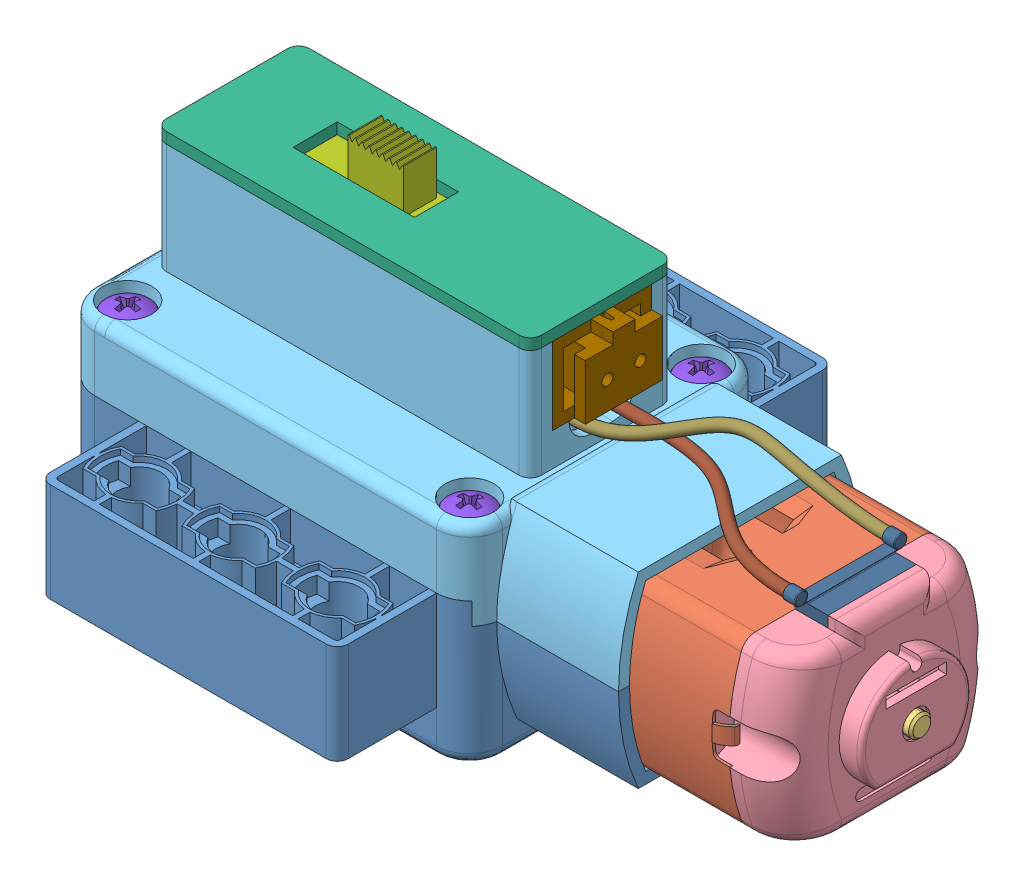
SolidWorks assembly Subconjunto motor, configuration Default. Lengths in mm.
Overall size (65.29 37.9 45).
23 component instances, 18 part files, 60 mates.
Components (placement in the parent):
- Caixa motor superior-1: Caixa motor superior [Default] at (12.9584 20.6455 40.0597) size (48 14.5 45)
- Carcaça-1: Carcaça [Default] at (41.4584 25.1455 40.0597) size (21 15 20.02)
- Veio rotor-1: Veio rotor [Default] at (40.9584 25.1455 40.0597) x (1 0 0) z (0 -0.655557 -0.755146) size (36 2 2)
- Tampa-1: Tampa [Default] at (52.4584 25.1455 40.0597) x (-1 0 0) z (0 0 -1) size (10.02 16 20.34)
- Caixa motor inferior-1: Caixa motor inferior [Default] at (12.9584 33.1455 40.0597) x (1 0 0) z (0 0 -1) size (48 22 27)
- Capa interruptor-1: Capa interruptor [Default] at (12.9584 43.1455 40.0597) size (34 8 13)
- Interruptor-1: Interruptor [Default] at (10.9428 42.1455 40.0597) size (18 5 6)
- pan head cross recess screw_iso-1: pan head cross recess screw_iso [ISO 7045 - M2 x 12 - Z - 12N] at (-2.5416 32.9855 50.5597) x (0 -1 0) z (0 0 1) size (13.57 4 4)
- pan head cross recess screw_iso-2: pan head cross recess screw_iso [ISO 7045 - M2 x 12 - Z - 12N] at (28.4584 32.9855 50.5597) x (0 -1 0) z (-0.094826 0 0.995494) size (13.57 4 4)
- pan head cross recess screw_iso-3: pan head cross recess screw_iso [ISO 7045 - M2 x 12 - Z - 12N] at (28.4584 32.9855 29.5597) x (0 -1 0) z (0 0 1) size (13.57 4 4)
- pan head cross recess screw_iso-4: pan head cross recess screw_iso [ISO 7045 - M2 x 12 - Z - 12N] at (-2.5416 32.9855 29.5597) x (0 -1 0) z (0 0 1) size (13.57 4 4)
- Ficha-1: Ficha [Default] at (31.9584 39.6455 40.0597) x (-1 0 0) z (0 0 -1) size (9 7 9)
- Terminais motor-1: Terminais motor [Default] at (52.9584 32.7705 40.0597) size (3 2.95 10.2)
- Part14^Subconjunto motor-1: Part14^Subconjunto motor [Default] at (27.9584 33.1455 40.0597) x (0 0 1) z (1 0 0) size (7.51 1.91 24.5)
- Part15^Subconjunto motor-1: Part15^Subconjunto motor [Default] at (27.9584 33.1455 40.0597) x (0 0 1) z (1 0 0) size (7.38 2.7 24.5)
- Veios interiores motor-1: Veios interiores motor [Veio cilindro menor] at (16.9584 22.6455 40.0597) x (0 1 0) z (0.959634 0 0.281251) size (19 2 2)
- Veios interiores motor-2: Veios interiores motor [Veio cilindro maior] at (5.9584 24.6955 40.0597) x (0 1 0) z (0 0 1) size (14.9 2 2)
- Engrenagem veio rotor-1: Engrenagem veio rotor [Default] at (25.6584 25.1455 40.0597) x (0 -0.542188 0.840257) z (0 -0.840257 -0.542188) size (6 5.02 6.03)
- 1º Engrenagem-1: 1º Engrenagem [Default] at (16.9584 29.7455 40.0597) x (-0.306597 0 -0.951839) z (-0.951839 0 0.306597) size (17.01 7.3 17.01)
- 2º e 3º Engrenagem-1: 2º e 3º Engrenagem [Default] at (5.9584 25.7455 40.0597) x (0.717197 0 -0.696871) z (-0.696871 0 -0.717197) size (17.4 6.4 17.38)
- 2º e 3º Engrenagem-2: 2º e 3º Engrenagem [Default] at (16.9584 22.0455 40.0597) x (-0.204507 0 -0.978865) z (-0.978865 0 0.204507) size (17.4 6.4 17.38)
- 4º Engrenagem-1: 4º Engrenagem [Default] at (5.9584 19.7455 40.0597) x (0.389423 0 -0.921059) z (-0.921059 0 -0.389423) size (17.4 3 17.4)
- Engrenagem saída do motor-1: Engrenagem saída do motor [Default] at (5.9584 18.2455 40.0597) x (0.962914 0 -0.269808) z (-0.269808 0 -0.962914) size (11.75 9 11.02)
Mates (geometry in assembly coordinates):
- Concentric1: concentric anti-aligned: cylinder of Carcaça-1 through (30.4584 25.1455 40.0597) axis (1 0 0) radius 3; cylinder of Veio rotor-1 through (22.9584 25.1455 40.0597) axis (-1 0 0) radius 1
- Concentric2: concentric anti-aligned: cylinder of Carcaça-1 through (30.4584 25.1455 40.0597) axis (1 0 0) radius 3; cylinder of Tampa-1 through (58.4584 25.1455 40.0597) axis (-1 0 0) radius 5
- Coincident1: coincident aligned: plane of Carcaça-1 through (51.4584 32.6455 48.6002) normal (0 1 0); plane of Tampa-1 through (48.4584 32.6455 31.5192) normal (0 1 0)
- Coincident2: coincident anti-aligned: plane of Carcaça-1 through (51.4584 25.1455 50.0597) normal (1 0 0); plane of Tampa-1 through (51.4584 17.6455 44.0597) normal (-1 0 0)
- Concentric3: concentric anti-aligned: cylinder of Caixa motor superior-1 through (-5.5426 25.1455 40.0597) axis (1 0 0) radius 3; cylinder of Veio rotor-1 through (22.9584 25.1455 40.0597) axis (-1 0 0) radius 1
- Coincident4: coincident aligned: plane of Caixa motor superior-1 through (30.4584 27.1455 50.5597) normal (-1 0 0); plane of Carcaça-1 through (30.4584 25.1455 40.0597) normal (-1 0 0)
- Distance1: distance = 0.5 mm aligned: plane of Tampa-1 through (58.4584 25.1455 40.0597) normal (1 0 0); plane of Veio rotor-1 through (58.9584 25.1455 40.0597) normal (1 0 0)
- Concentric4: concentric anti-aligned: cylinder of Caixa motor superior-1 through (18.4584 27.1455 28.5097) axis (0 -1 0) radius 1; cylinder of Caixa motor inferior-1 through (18.4584 21.1455 28.5097) axis (0 1 0) radius 1
- Concentric5: concentric anti-aligned: cylinder of Caixa motor superior-1 through (7.4584 27.1455 51.6097) axis (0 -1 0) radius 1; cylinder of Caixa motor inferior-1 through (7.4584 21.1455 51.6097) axis (0 1 0) radius 1
- Coincident6: coincident anti-aligned: plane of Caixa motor superior-1 through (28.4584 27.1455 50.5597) normal (0 1 0); plane of Caixa motor inferior-1 through (28.4584 27.1455 50.5597) normal (0 -1 0)
- Width1: width anti-aligned: plane of Capa interruptor-1 through (3.9584 36.1455 38.0597) normal (0 0 1); plane of Capa interruptor-1 through (3.9584 36.1455 42.0597) normal (0 0 -1); plane of Interruptor-1 through (8.4428 47.1455 38.5597) normal (0 0 -1); plane of Interruptor-1 through (8.4428 47.1455 41.5597) normal (0 0 1)
- Coincident7: coincident anti-aligned: plane of Capa interruptor-1 through (28.9584 43.1455 34.5597) normal (0 -1 0); plane of Interruptor-1 through (10.9428 43.1455 40.0597) normal (0 1 0)
- LimitDistance1: limit distance = 1.5156 mm anti-aligned: plane of Interruptor-1 through (13.4428 47.1455 38.5597) normal (1 0 0); plane of Capa interruptor-1 through (14.9584 36.1455 42.0597) normal (-1 0 0)
- Concentric6: concentric anti-aligned: cylinder of Caixa motor inferior-1 through (-2.2916 46.1455 44.8097) axis (0 -1 0) radius 0.5; cylinder of Capa interruptor-1 through (-2.2916 36.1455 44.8097) axis (0 1 0) radius 0.5
- Concentric7: concentric anti-aligned: cylinder of Caixa motor inferior-1 through (21.2084 46.1455 35.3097) axis (0 -1 0) radius 0.5; cylinder of Capa interruptor-1 through (21.2084 36.1455 35.3097) axis (0 1 0) radius 0.5
- Coincident8: coincident anti-aligned: plane of Caixa motor inferior-1 through (-3.0416 43.1455 34.5597) normal (0 1 0); plane of Capa interruptor-1 through (28.9584 43.1455 34.5597) normal (0 -1 0)
- Concentric8: concentric aligned: cylinder of Caixa motor inferior-1 through (-2.5416 33.1455 50.5597) axis (0 1 0) radius 1.2; cylinder of pan head cross recess screw_iso-1 through (-2.5416 58.3855 50.5597) axis (0 1 0) radius 2
- Coincident9: coincident anti-aligned: plane of Caixa motor inferior-1 through (-2.5416 31.3855 50.5597) normal (0 1 0); plane of pan head cross recess screw_iso-1 through (-1.5416 31.3855 50.5597) normal (0 -1 0)
- Concentric9: concentric aligned: cylinder of Caixa motor inferior-1 through (28.4584 33.1455 50.5597) axis (0 1 0) radius 1.2; cylinder of pan head cross recess screw_iso-2 through (28.4584 58.3855 50.5597) axis (0 1 0) radius 2
- Coincident10: coincident anti-aligned: plane of Caixa motor inferior-1 through (28.4584 31.3855 50.5597) normal (0 1 0); plane of pan head cross recess screw_iso-2 through (29.4539 31.3855 50.6545) normal (0 -1 0)
- Concentric10: concentric aligned: cylinder of Caixa motor inferior-1 through (28.4584 33.1455 29.5597) axis (0 1 0) radius 1.2; cylinder of pan head cross recess screw_iso-3 through (28.4584 58.3855 29.5597) axis (0 1 0) radius 2
- Coincident11: coincident anti-aligned: plane of Caixa motor inferior-1 through (28.4584 31.3855 29.5597) normal (0 1 0); plane of pan head cross recess screw_iso-3 through (29.4584 31.3855 29.5597) normal (0 -1 0)
- Concentric11: concentric aligned: cylinder of Caixa motor inferior-1 through (-2.5416 33.1455 29.5597) axis (0 1 0) radius 1.2; cylinder of pan head cross recess screw_iso-4 through (-2.5416 58.3855 29.5597) axis (0 1 0) radius 2
- Coincident12: coincident anti-aligned: plane of Caixa motor inferior-1 through (-2.5416 31.3855 29.5597) normal (0 1 0); plane of pan head cross recess screw_iso-4 through (-1.5416 31.3855 29.5597) normal (0 -1 0)
- Coincident13: coincident anti-aligned: plane of Caixa motor inferior-1 through (22.9584 33.1455 40.0597) normal (1 0 0); plane of Ficha-1 through (22.9584 39.6455 40.0597) normal (-1 0 0)
- Coincident14: coincident anti-aligned: plane of Caixa motor inferior-1 through (22.9584 43.1455 44.5597) normal (0 0 -1); plane of Ficha-1 through (29.9584 36.1455 44.5597) normal (0 0 1)
- Coincident15: coincident anti-aligned: plane of Caixa motor inferior-1 through (22.9584 36.1455 35.5597) normal (0 1 0); plane of Ficha-1 through (29.9584 36.1455 44.5597) normal (0 -1 0)
- Concentric12: concentric anti-aligned: cylinder of Tampa-1 through (54.4584 32.7705 40.0597) axis (1 0 0) radius 0.5; cylinder of Terminais motor-1 through (54.4584 32.7705 40.0597) axis (-1 0 0) radius 0.5
- Coincident16: coincident anti-aligned: plane of Tampa-1 through (54.4584 17.6445 44.0597) normal (-1 0 0); plane of Terminais motor-1 through (54.4584 32.7705 40.0597) normal (1 0 0)
- Coincident17: coincident anti-aligned: plane of Carcaça-1 through (51.4584 32.6455 48.6002) normal (0 1 0); plane of Caixa motor inferior-1 through (9.0982 32.6455 40.0597) normal (0 -1 0)
- Coincident18: coincident aligned: plane of Tampa-1 through (56.4584 33.6455 36.0597) normal (0 1 0); plane of Terminais motor-1 through (54.4584 33.6455 44.0597) normal (0 1 0)
- InPlace6: in place: plane of Caixa motor inferior-1 through (27.9584 35.1455 38.5597) normal (1 0 0); plane of ? through (27.9584 0 0) normal (1 0 0); moOrthogonalPlaneRef_w of Caixa motor inferior-1 through (27.9584 35.1455 38.5597) normal (1 0 0); plane of ? through (27.9584 0 0) normal (0 1 0); plane of Caixa motor inferior-1 through (27.9584 35.1455 38.5597) normal (1 0 0); plane of ? through (27.9584 0 0) normal (0 0 -1); plane of Caixa motor inferior-1 through (27.9584 35.1455 38.5597) normal (1 0 0); unknown of ?
- Coincident34: coincident aligned: plane of Caixa motor inferior-1; plane of Part14^Subconjunto motor-1
- Coincident35: coincident aligned: moOrthogonalPlaneRef_w of Caixa motor inferior-1 through (27.9584 33.1455 40.0597) normal (0 -1 0); plane of Part14^Subconjunto motor-1 through (27.9584 33.1455 40.0597) normal (0 -1 0)
- Coincident36: coincident anti-aligned: moOrthogonalPlaneRef_w of Caixa motor inferior-1 through (27.9584 33.1455 40.0597) normal (0 0 -1); plane of Part14^Subconjunto motor-1 through (27.9584 33.1455 40.0597) normal (0 0 1)
- InPlace7: in place: plane of Caixa motor inferior-1 through (27.9584 35.1455 41.5597) normal (1 0 0); plane of ? through (27.9584 0 0) normal (1 0 0); plane of Caixa motor inferior-1 through (27.9584 35.1455 41.5597) normal (1 0 0); plane of ? through (27.9584 0 0) normal (0 1 0); plane of Caixa motor inferior-1 through (27.9584 35.1455 41.5597) normal (1 0 0); plane of ? through (27.9584 0 0) normal (0 0 -1); plane of Caixa motor inferior-1 through (27.9584 35.1455 41.5597) normal (1 0 0); unknown of ?
- Coincident37: coincident aligned: plane of Caixa motor inferior-1; plane of Part15^Subconjunto motor-1
- Coincident38: coincident aligned: moOrthogonalPlaneRef_w of Caixa motor inferior-1 through (27.9584 33.1455 40.0597) normal (0 -1 0); plane of Part15^Subconjunto motor-1 through (27.9584 33.1455 40.0597) normal (0 -1 0)
- Coincident39: coincident anti-aligned: moOrthogonalPlaneRef_w of Caixa motor inferior-1 through (27.9584 33.1455 40.0597) normal (0 0 -1); plane of Part15^Subconjunto motor-1 through (27.9584 33.1455 40.0597) normal (0 0 1)
- Concentric13: concentric anti-aligned: cylinder of Caixa motor inferior-1 through (5.9584 26.1455 40.0597) axis (0 1 0) radius 1; cylinder of Veios interiores motor-2 through (5.9584 32.1455 40.0597) axis (0 -1 0) radius 1
- Coincident19: coincident anti-aligned: plane of Caixa motor inferior-1 through (28.4584 32.1455 50.5597) normal (0 -1 0); plane of Veios interiores motor-2 through (5.9584 32.1455 40.0597) normal (0 1 0)
- Concentric14: concentric anti-aligned: cylinder of Caixa motor inferior-1 through (16.9584 29.7455 40.0597) axis (0 1 0) radius 1; cylinder of Veios interiores motor-1 through (16.9584 32.1455 40.0597) axis (0 -1 0) radius 1
- Coincident20: coincident anti-aligned: plane of Caixa motor inferior-1 through (28.4584 32.1455 50.5597) normal (0 -1 0); plane of Veios interiores motor-1 through (16.9584 32.1455 40.0597) normal (0 1 0)
- Concentric15: concentric anti-aligned: cylinder of Veio rotor-1 through (22.9584 25.1455 40.0597) axis (-1 0 0) radius 1; cylinder of Engrenagem veio rotor-1 through (23.1584 25.1455 40.0597) axis (1 0 0) radius 1
- Coincident21: coincident anti-aligned: circle of Veio rotor-1; plane of Engrenagem veio rotor-1 through (23.1584 25.1455 40.0597) normal (-1 0 0)
- Concentric16: concentric aligned: cylinder of Veios interiores motor-1 through (16.9584 32.1455 40.0597) axis (0 -1 0) radius 1; cylinder of 1º Engrenagem-1 through (16.9584 29.7455 40.0597) axis (0 -1 0) radius 1
- Coincident22: coincident anti-aligned: plane of Caixa motor inferior-1 through (16.9584 29.7455 40.0597) normal (0 -1 0); plane of 1º Engrenagem-1 through (16.9584 29.7455 40.0597) normal (0 1 0)
- GearMate1: gear = 32 : 10 mm: cylinder of Engrenagem veio rotor-1 through (23.1584 25.1455 40.0597) axis (1 0 0) radius 1.5; cylinder of 1º Engrenagem-1 through (16.9584 28.7455 40.0597) axis (0 1 0) radius 8.5
- Concentric17: concentric aligned: cylinder of Veios interiores motor-2 through (5.9584 32.1455 40.0597) axis (0 -1 0) radius 1; cylinder of 2º e 3º Engrenagem-1 through (5.9584 25.7455 40.0597) axis (0 -1 0) radius 1
- Coincident23: coincident anti-aligned: plane of Caixa motor inferior-1 through (5.9584 26.1455 40.0597) normal (0 -1 0); plane of 2º e 3º Engrenagem-1 through (5.9584 26.1455 40.0597) normal (0 1 0)
- GearMate2: gear = 9 : 35 mm: cylinder of 2º e 3º Engrenagem-1 through (5.9584 23.7455 40.0597) axis (0 1 0) radius 7.5; cylinder of 1º Engrenagem-1 through (16.9584 22.4455 40.0597) axis (0 1 0) radius 1.5
- Concentric18: concentric aligned: cylinder of Veios interiores motor-1 through (16.9584 32.1455 40.0597) axis (0 -1 0) radius 1; cylinder of 2º e 3º Engrenagem-2 through (16.9584 22.0455 40.0597) axis (0 -1 0) radius 1
- Coincident24: coincident anti-aligned: plane of 1º Engrenagem-1 through (16.9584 22.4455 40.0597) normal (0 -1 0); plane of 2º e 3º Engrenagem-2 through (16.9584 22.4455 40.0597) normal (0 1 0)
- GearMate3: gear = 35 : 9 mm: cylinder of 2º e 3º Engrenagem-1 through (5.9584 19.7455 40.0597) axis (0 1 0) radius 1.5; cylinder of 2º e 3º Engrenagem-2 through (16.9584 20.0455 40.0597) axis (0 1 0) radius 7.5
- Concentric19: concentric aligned: cylinder of Veios interiores motor-2 through (5.9584 32.1455 40.0597) axis (0 -1 0) radius 1; cylinder of 4º Engrenagem-1 through (5.9584 19.7455 40.0597) axis (0 -1 0) radius 1
- GearMate4: gear = 9 : 36 mm: cylinder of 4º Engrenagem-1 through (5.9584 16.7455 40.0597) axis (0 1 0) radius 7.5; cylinder of 2º e 3º Engrenagem-2 through (16.9584 16.0455 40.0597) axis (0 1 0) radius 1.5
- Coincident25: coincident anti-aligned: plane of 2º e 3º Engrenagem-1 through (5.9584 19.7455 40.0597) normal (0 -1 0); plane of 4º Engrenagem-1 through (5.9584 19.7455 40.0597) normal (0 1 0)
- Concentric21: concentric anti-aligned: cylinder of Veios interiores motor-2 through (5.9584 32.1455 40.0597) axis (0 -1 0) radius 1; cylinder of Engrenagem saída do motor-1 through (5.9584 13.9171 40.0597) axis (0 1 0) radius 1
- Concentric22: concentric anti-aligned: cylinder of 4º Engrenagem-1 through (9.2297 18.2455 43.7746) axis (0 -1 0) radius 1.05; cylinder of Engrenagem saída do motor-1 through (9.2297 16.7455 43.7746) axis (0 1 0) radius 1.05
- Coincident26: coincident anti-aligned: plane of 4º Engrenagem-1 through (5.9584 18.2455 40.0597) normal (0 -1 0); plane of Engrenagem saída do motor-1 through (5.9584 18.2455 40.0597) normal (0 1 0)
